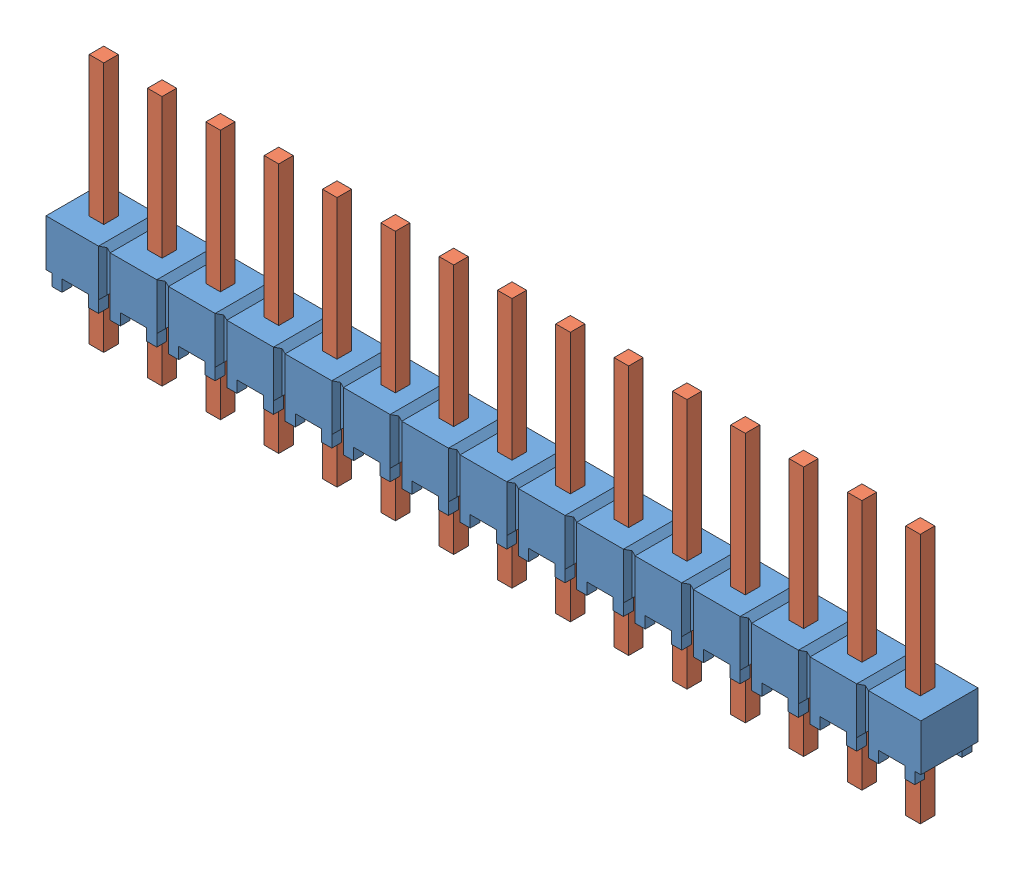
SolidWorks assembly HMTSW_115_07_G_S_240, configuration Default. Lengths in mm.
Overall size (38.1 10.92 2.49).
2 component instances, 2 part files, 0 mates.
Components (placement in the parent):
- _HMTSW_115_07_G_S_240_body_2-1: _HMTSW_115_07_G_S_240_body_2 [Default] at origin size (38.1 2.54 2.49)
- _HMTSW_115_07_S_240_4-1: _HMTSW_115_07_S_240_4 [Default] at (0 -2.286 0) size (36.45 10.92 0.89)
